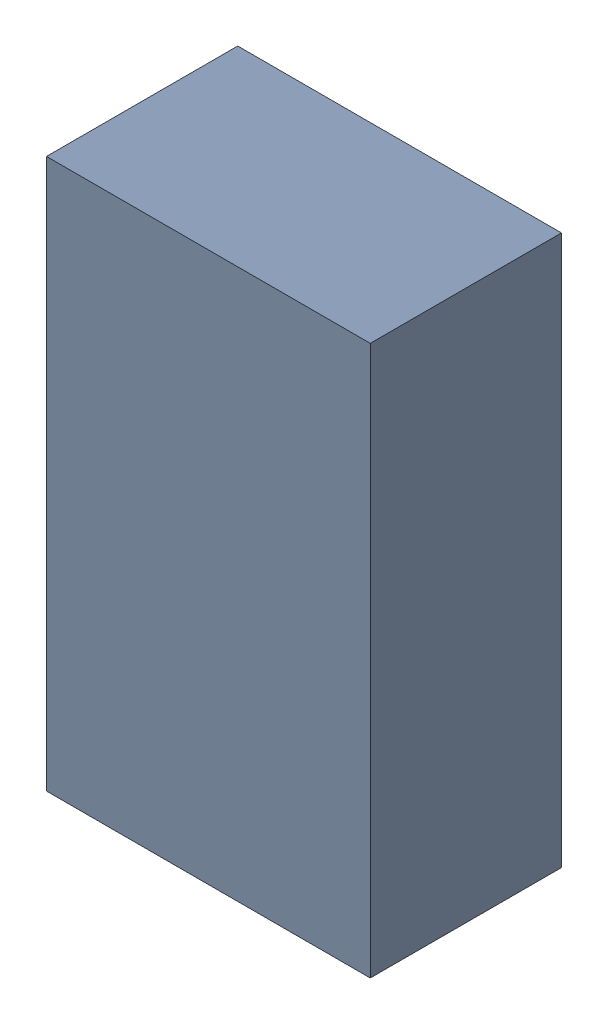
SolidWorks assembly 6327396736, configuration Default. Lengths in mm.
Overall size (0.43 0.73 0.25).
2 component instances, 1 part files, 0 mates.
Components (placement in the parent):
- 6701982208-1:  [Default] at (27.7 14.8 0) (suppressed, hidden)
- Extruded-2-1: Extruded-2 [Default] at origin size (0.43 0.73 0.25)
